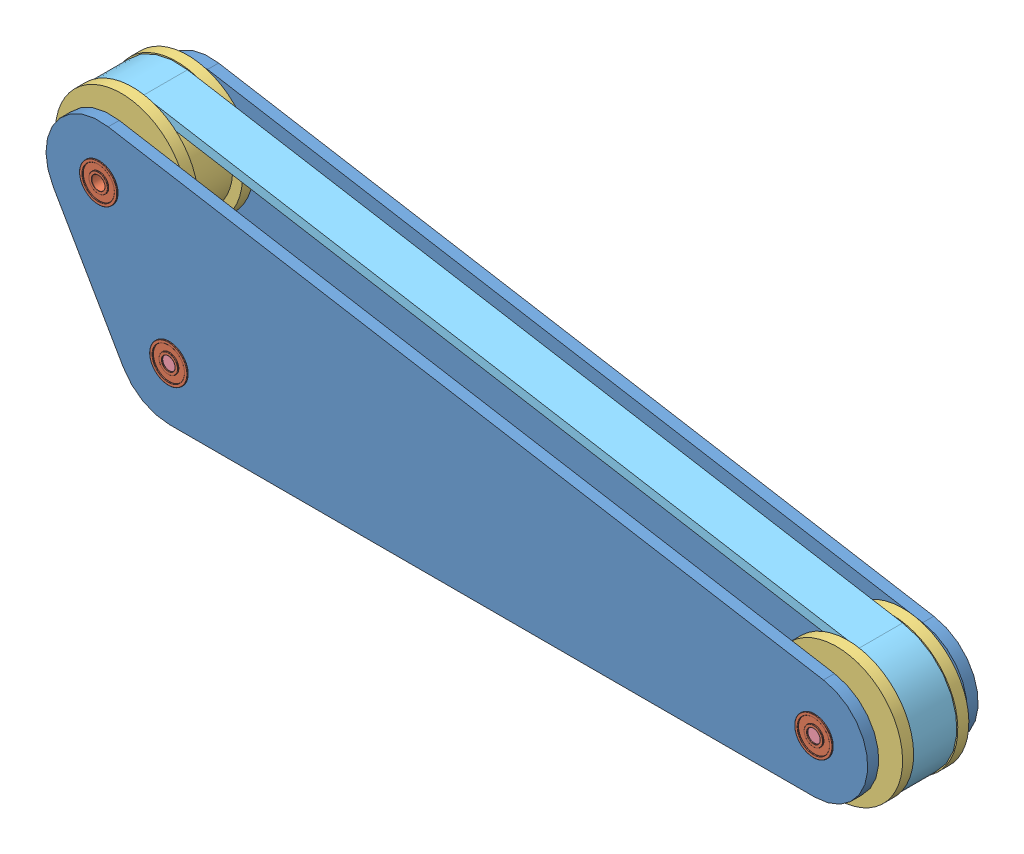
SolidWorks assembly Latest, configuration Default. Lengths in mm.
Overall size (393.53 124.67 51).
14 component instances, 5 part files, 25 mates.
Components (placement in the parent):
- Frame For Belt-1: Frame For Belt [Default] at origin size (372.11 103.25 5)
- 606-2RS  HCH ball bearing-1: 606-2RS  HCH ball bearing [Default] at (0 0 2.5) x (0.802492 0.596663 0) z (0 0 1) size (17 17 6)
- 606-2RS  HCH ball bearing-2: 606-2RS  HCH ball bearing [Default] at (-31.75 54.9926 2.5) x (0.888226 -0.459406 0) z (0 0 1) size (17 17 6)
- 606-2RS  HCH ball bearing-3: 606-2RS  HCH ball bearing [Default] at (292.1 0 2.5) x (0.802492 0.596663 0) z (0 0 1) size (17 17 6)
- 2in Pulley-1: 2in Pulley [Default] at (0 0 -20) x (-0.999623 -0.027449 0) z (0 0 1) size (59.8 59.8 30)
- 2in Pulley-2: 2in Pulley [Default] at (-31.75 54.9926 -20) x (0.057104 0.998368 0) z (0 0 1) size (59.8 59.8 30)
- 2in Pulley-3: 2in Pulley [Default] at (292.1 0 -20) x (-0.943457 0.331496 0) z (0 0 1) size (59.8 59.8 30)
- 1.97 inch-1: 1.97 inch [Default] at (0 0 -45) size (6 6 50.04)
- 1.97 inch-2: 1.97 inch [Default] at (292.1 0 -45.038) size (6 6 50.04)
- Frame For Belt-2: Frame For Belt [Default] at (0 0 -45) size (372.11 103.25 5)
- 606-2RS  HCH ball bearing-4: 606-2RS  HCH ball bearing [Default] at (-31.75 54.9926 -42.5) size (17 17 6)
- 606-2RS  HCH ball bearing-5: 606-2RS  HCH ball bearing [Default] at (292.1 0 -42.5) size (17 17 6)
- 606-2RS  HCH ball bearing-6: 606-2RS  HCH ball bearing [Default] at (0 0 -42.5) size (17 17 6)
- Belt1-1-1: Belt1-1 [Default] at (-31.75 54.9926 -20) x (-1 0 0) z (0 0 -1) size (382.85 113.99 20)
Mates (geometry in assembly coordinates):
- Concentric1: concentric aligned: cylinder of Frame For Belt-1 through (0 0 5) axis (0 0 -1) radius 8.5; cylinder of 606-2RS  HCH ball bearing-1 through (0 0 5.5) axis (0 0 -1) radius 8.5
- Coincident1: coincident aligned: plane of Frame For Belt-1 through (-31.75 54.9926 5) normal (0 0 1); plane of 606-2RS  HCH ball bearing-1 through (0 0 5) normal (0 0 1)
- Concentric2: concentric aligned: cylinder of Frame For Belt-1 through (-31.75 54.9926 5) axis (0 0 -1) radius 8.5; cylinder of 606-2RS  HCH ball bearing-2 through (-31.75 54.9926 5.5) axis (0 0 -1) radius 8.5
- Coincident2: coincident aligned: plane of Frame For Belt-1 through (-31.75 54.9926 5) normal (0 0 1); plane of 606-2RS  HCH ball bearing-2 through (-31.75 54.9926 5) normal (0 0 1)
- Concentric4: concentric aligned: cylinder of Frame For Belt-1 through (292.1 0 5) axis (0 0 -1) radius 8.5; cylinder of 606-2RS  HCH ball bearing-3 through (292.1 0 5.5) axis (0 0 -1) radius 8.5
- Coincident3: coincident aligned: plane of Frame For Belt-1 through (-31.75 54.9926 5) normal (0 0 1); plane of 606-2RS  HCH ball bearing-3 through (292.1 0 5) normal (0 0 1)
- Concentric6: concentric anti-aligned: cylinder of 606-2RS  HCH ball bearing-1 through (0 0 5.5) axis (0 0 -1) radius 3; cylinder of 2in Pulley-1 through (0 0 -81.628) axis (0 0 1) radius 3
- Coincident6: coincident aligned: plane of 2in Pulley-1 through (0 0 -35) normal (0 0 -1); plane of 2in Pulley-2 through (-31.75 54.9926 -35) normal (0 0 -1)
- Concentric7: concentric anti-aligned: cylinder of 606-2RS  HCH ball bearing-2 through (-31.75 54.9926 5.5) axis (0 0 -1) radius 3; cylinder of 2in Pulley-2 through (-31.75 54.9926 -81.628) axis (0 0 1) radius 3
- Coincident7: coincident aligned: plane of 2in Pulley-2 through (-31.75 54.9926 -35) normal (0 0 -1); plane of 2in Pulley-3 through (292.1 0 -35) normal (0 0 -1)
- Concentric8: concentric anti-aligned: cylinder of 606-2RS  HCH ball bearing-3 through (292.1 0 5.5) axis (0 0 -1) radius 3; cylinder of 2in Pulley-3 through (292.1 0 -81.628) axis (0 0 1) radius 3
- Distance1: distance = 5 mm anti-aligned: plane of Frame For Belt-1 through (-31.75 54.9926 0) normal (0 0 -1); plane of 2in Pulley-3 through (292.1 0 -5) normal (0 0 1)
- Concentric14: concentric aligned: cylinder of 606-2RS  HCH ball bearing-3 through (292.1 0 5.5) axis (0 0 -1) radius 3; cylinder of 1.97 inch-2 through (292.1 0 5) axis (0 0 -1) radius 3
- Coincident9: coincident aligned: plane of Frame For Belt-1 through (-31.75 54.9926 5) normal (0 0 1); plane of 1.97 inch-2 through (292.1 0 5) normal (0 0 1)
- Coincident10: coincident aligned: plane of Frame For Belt-1 through (-52.6472 42.9276 0) normal (-0.866025 -0.5 0); plane of Frame For Belt-2 through (-52.6472 42.9276 -45) normal (-0.866025 -0.5 0)
- Coincident11: coincident aligned: plane of Frame For Belt-1 through (296.1397 23.7895 0) normal (0.167412 0.985887 0); plane of Frame For Belt-2 through (296.1397 23.7895 -45) normal (0.167412 0.985887 0)
- Distance2: distance = 5 mm anti-aligned: plane of Frame For Belt-2 through (-31.75 54.9926 -40) normal (0 0 1); plane of 2in Pulley-2 through (-31.75 54.9926 -35) normal (0 0 -1)
- Coincident13: coincident aligned: plane of 606-2RS  HCH ball bearing-4 through (-31.75 54.9926 -45) normal (0 0 -1); plane of 606-2RS  HCH ball bearing-5 through (292.1 0 -45) normal (0 0 -1)
- Coincident14: coincident aligned: plane of 606-2RS  HCH ball bearing-4 through (-31.75 54.9926 -45) normal (0 0 -1); plane of 606-2RS  HCH ball bearing-6 through (0 0 -45) normal (0 0 -1)
- Coincident15: coincident aligned: plane of Frame For Belt-2 through (-31.75 54.9926 -45) normal (0 0 -1); plane of 606-2RS  HCH ball bearing-4 through (-31.75 54.9926 -45) normal (0 0 -1)
- Concentric19: concentric aligned: cylinder of Frame For Belt-2 through (-31.75 54.9926 -40) axis (0 0 -1) radius 8.5; cylinder of 606-2RS  HCH ball bearing-4 through (-31.75 54.9926 -39.5) axis (0 0 -1) radius 8.5
- Concentric20: concentric aligned: cylinder of Frame For Belt-2 through (0 0 -40) axis (0 0 -1) radius 8.5; cylinder of 606-2RS  HCH ball bearing-6 through (0 0 -39.5) axis (0 0 -1) radius 8.5
- Concentric21: concentric aligned: cylinder of Frame For Belt-2 through (292.1 0 -40) axis (0 0 -1) radius 8.5; cylinder of 606-2RS  HCH ball bearing-5 through (292.1 0 -39.5) axis (0 0 -1) radius 8.5
- BeltMate1: belt = 50.8 : 50.8 mm: cylinder of 2in Pulley-2 through (-31.75 54.9926 -10) axis (0 0 -1) radius 25.4; cylinder of 2in Pulley-1 through (0 0 -10) axis (0 0 -1) radius 25.4
- BeltMate2: belt = 50.8 : 50.8 mm: cylinder of 2in Pulley-1 through (0 0 -10) axis (0 0 -1) radius 25.4; cylinder of 2in Pulley-3 through (292.1 0 -10) axis (0 0 -1) radius 25.4
